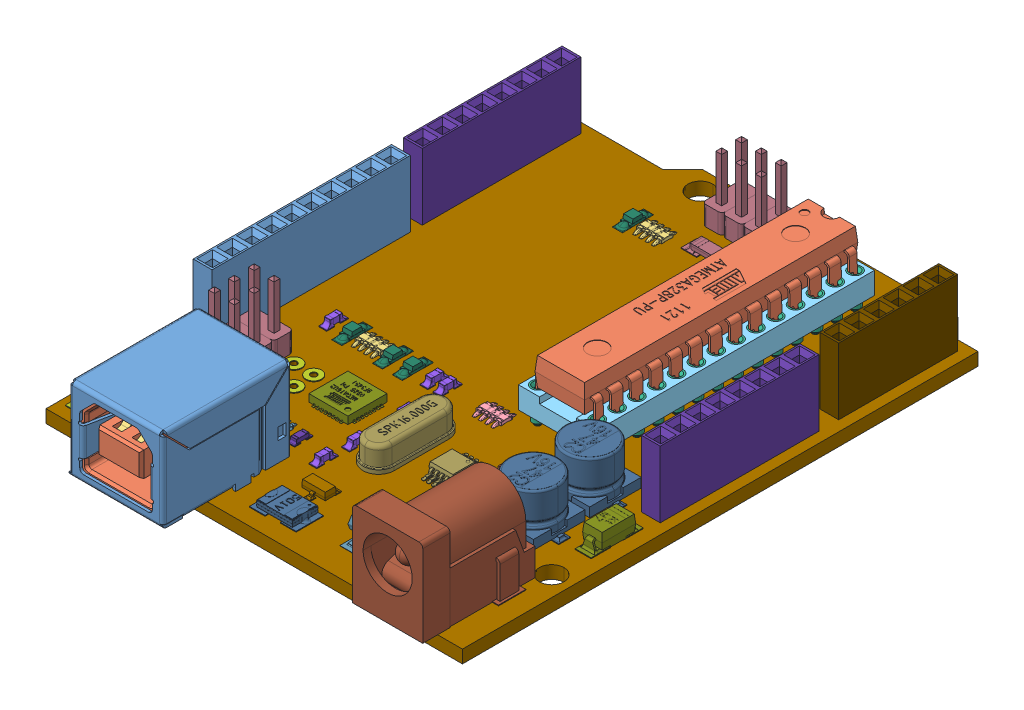
SolidWorks assembly arduino uno, configuration Default. Lengths in mm.
Overall size (53.34 15.26 74.94).
88 component instances, 35 part files, 0 mates.
Components (placement in the parent):
- arduino uno.STEP-1: arduino uno.STEP [Default] at origin size (53.34 15.26 74.94)
  - USB type b.STEP-1: USB type b.STEP [Default] at (-38.02 0.43 6.35) size (13.91 15.21 16.51)
    - USB SHELL.STEP-1: USB SHELL.STEP [Default] at origin size (13.91 15.21 16.51)
    - USB core.STEP-1: USB core.STEP [Default] at origin size (11.3 10.68 15.75)
    - usb top contact.STEP-1: usb top contact.STEP [Default] at (1.25 6.09 -0.38) size (1 9.67 13.76)
    - usb btm contact.STEP-1: usb btm contact.STEP [Default] at (1.25 4.41 -0.38) size (1 6.84 11.76)
    - usb btm contact.STEP-2: usb btm contact.STEP [Default] at (-1.25 4.41 -0.38) size (1 6.84 11.76)
    - usb top contact.STEP-2: usb top contact.STEP [Default] at (-1.25 6.09 -0.38) size (1 9.67 13.76)
  - dip28.STEP-1: dip28.STEP [Default] at (-16.383 1.5 -46.355) x (0 0 -1) z (1 0 0) size (35.48 7.37 10.1)
    - dip28-0.STEP-1: dip28-0.STEP [Default] at origin size (35.48 2.8 10.1)
    - dip socket pin.STEP-1: dip socket pin.STEP [Default] at (16.51 2.8 -3.81) size (1.7 7.37 1.7)
    - dip socket pin.STEP-2: dip socket pin.STEP [Default] at (16.51 2.8 3.81) size (1.7 7.37 1.7)
    - dip socket pin.STEP-3: dip socket pin.STEP [Default] at (13.97 2.8 -3.81) size (1.7 7.37 1.7)
    - dip socket pin.STEP-4: dip socket pin.STEP [Default] at (13.97 2.8 3.81) size (1.7 7.37 1.7)
    - dip socket pin.STEP-5: dip socket pin.STEP [Default] at (11.43 2.8 -3.81) size (1.7 7.37 1.7)
    - dip socket pin.STEP-6: dip socket pin.STEP [Default] at (11.43 2.8 3.81) size (1.7 7.37 1.7)
    - dip socket pin.STEP-7: dip socket pin.STEP [Default] at (8.89 2.8 -3.81) size (1.7 7.37 1.7)
    - dip socket pin.STEP-8: dip socket pin.STEP [Default] at (8.89 2.8 3.81) size (1.7 7.37 1.7)
    - dip socket pin.STEP-9: dip socket pin.STEP [Default] at (6.35 2.8 -3.81) size (1.7 7.37 1.7)
    - dip socket pin.STEP-10: dip socket pin.STEP [Default] at (6.35 2.8 3.81) size (1.7 7.37 1.7)
    - dip socket pin.STEP-11: dip socket pin.STEP [Default] at (3.81 2.8 -3.81) size (1.7 7.37 1.7)
    - dip socket pin.STEP-12: dip socket pin.STEP [Default] at (3.81 2.8 3.81) size (1.7 7.37 1.7)
    - dip socket pin.STEP-13: dip socket pin.STEP [Default] at (1.27 2.8 -3.81) size (1.7 7.37 1.7)
    - dip socket pin.STEP-14: dip socket pin.STEP [Default] at (1.27 2.8 3.81) size (1.7 7.37 1.7)
    - dip socket pin.STEP-15: dip socket pin.STEP [Default] at (-1.27 2.8 -3.81) size (1.7 7.37 1.7)
    - dip socket pin.STEP-16: dip socket pin.STEP [Default] at (-1.27 2.8 3.81) size (1.7 7.37 1.7)
    - dip socket pin.STEP-17: dip socket pin.STEP [Default] at (-3.81 2.8 -3.81) size (1.7 7.37 1.7)
    - dip socket pin.STEP-18: dip socket pin.STEP [Default] at (-3.81 2.8 3.81) size (1.7 7.37 1.7)
    - dip socket pin.STEP-19: dip socket pin.STEP [Default] at (-6.35 2.8 -3.81) size (1.7 7.37 1.7)
    - dip socket pin.STEP-20: dip socket pin.STEP [Default] at (-6.35 2.8 3.81) size (1.7 7.37 1.7)
    - dip socket pin.STEP-21: dip socket pin.STEP [Default] at (-8.89 2.8 -3.81) size (1.7 7.37 1.7)
    - dip socket pin.STEP-22: dip socket pin.STEP [Default] at (-8.89 2.8 3.81) size (1.7 7.37 1.7)
    - dip socket pin.STEP-23: dip socket pin.STEP [Default] at (-11.43 2.8 -3.81) size (1.7 7.37 1.7)
    - dip socket pin.STEP-24: dip socket pin.STEP [Default] at (-11.43 2.8 3.81) size (1.7 7.37 1.7)
    - dip socket pin.STEP-25: dip socket pin.STEP [Default] at (-13.97 2.8 -3.81) size (1.7 7.37 1.7)
    - dip socket pin.STEP-26: dip socket pin.STEP [Default] at (-13.97 2.8 3.81) size (1.7 7.37 1.7)
    - dip socket pin.STEP-27: dip socket pin.STEP [Default] at (-16.51 2.8 -3.81) size (1.7 7.37 1.7)
    - dip socket pin.STEP-28: dip socket pin.STEP [Default] at (-16.51 2.8 3.81) size (1.7 7.37 1.7)
  - RESET BUTTON.STEP-1: RESET BUTTON.STEP [Default] at (-49.403 0 -6.35) size (6.2 3.1 9.6)
    - RESET CORE.STEP-1: RESET CORE.STEP [Default] at (0 0.1 0) x (-1 0 0) z (0 0 -1) size (6.2 3.1 9.6)
    - RESET.STEP-1: RESET.STEP [Default] at (0 0.1 0) x (0 0 1) z (-1 0 0) size (7.3 2 6.2)
  - unoboard blue.STEP-1: unoboard blue.STEP [Default] at origin size (53.34 1.65 68.58)
  - 47uf CAP Dcase.STEP-1: 47uf CAP Dcase.STEP [Default] at (-9.4141 0 -18.4991) x (0 0 -1) z (1 0 0) size (6.6 5.81 8)
  - power jack.STEP-1: power jack.STEP [Default] at (-7.675 0 1.905) size (11.2 15.2 15.9)
  - 47uf CAP Dcase.STEP-2: 47uf CAP Dcase.STEP [Default] at (-9.4141 0 -25.7132) x (0 0 -1) z (1 0 0) size (6.6 5.81 8)
  - crystal.STEP-1: crystal.STEP [Default] at (-26.162 0 -18.923) x (1 0 0) z (0 0 -1) size (4 5 11)
  - 2pin_header__02.STEP-1: 2pin_header__02.STEP [Default] at (-46.23 0 -15.75) size (5 11.75 2.54)
  - nano - reg.STEP-1: nano - reg.STEP [Default] at (-17.399 0 -7.747) size (6.5 1.69 8.3)
  - led.STEP-1: led.STEP [Default] at (-34.29 0 -27.94) x (0 0 1) z (-1 0 0) size (4 0.85 1.47)
  - 2pin_header__02.STEP-2: 2pin_header__02.STEP [Default] at (-30.43 0 -64.91) x (0 0 1) z (-1 0 0) size (5 11.75 2.54)
  - 2pin_header__02.STEP-3: 2pin_header__02.STEP [Default] at (-27.89 0 -64.91) x (0 0 1) z (-1 0 0) size (5 11.75 2.54)
  - 2pin_header__02.STEP-4: 2pin_header__02.STEP [Default] at (-25.35 0 -64.91) x (0 0 1) z (-1 0 0) size (5 11.75 2.54)
  - 2pin_header__02.STEP-5: 2pin_header__02.STEP [Default] at (-46.23 0 -18.29) size (5 11.75 2.54)
  - 2pin_header__02.STEP-6: 2pin_header__02.STEP [Default] at (-46.23 0 -20.83) size (5 11.75 2.54)
  - atmega16u2.STEP-1: atmega16u2.STEP [Default] at (-34.671 0.06 -20) x (1 0 0) z (0 0 -1) size (5.5 1.01 5.5)
  - led.STEP-2: led.STEP [Default] at (-36.83 0 -27.94) x (0 0 1) z (-1 0 0) size (4 0.85 1.47)
  - led.STEP-3: led.STEP [Default] at (-42.037 0 -27.94) x (0 0 1) z (-1 0 0) size (4 0.85 1.47)
  - led.STEP-4: led.STEP [Default] at (-36.576 0 -58.42) x (0 0 1) z (-1 0 0) size (4 0.85 1.47)
  - 8 PORT HEADER.STEP-1: 8 PORT HEADER.STEP [Default] at (-50.8 0 -45.72) x (0 0 -1) z (1 0 0) size (20.32 10.51 2.41)
  - 8 PORT HEADER.STEP-2: 8 PORT HEADER.STEP [Default] at (-2.54 0 -27.94) x (0 0 -1) z (1 0 0) size (20.32 10.51 2.41)
  - 6 PORT HEADER.STEP-1: 6 PORT HEADER.STEP [Default] at (-2.54 0 -50.8) x (0 0 -1) z (1 0 0) size (15.24 10.51 2.41)
  - 10 PORT HEADER.STEP-1: 10 PORT HEADER.STEP [Default] at (-50.8 0 -18.796) x (0 0 -1) z (1 0 0) size (25.4 10.51 2.41)
  - ATMEL328P.STEP-1: ATMEL328P.STEP [Default] at (-16.383 4.3 -46.355) x (0 0 -1) z (1 0 0) size (35 7.27 7.87)
  - 102 RESISTOR PACK.STEP-1: 102 RESISTOR PACK.STEP [Default] at (-33.782 0 -58.42) size (3.2 0.46 3)
  - 102 RESISTOR PACK.STEP-2: 102 RESISTOR PACK.STEP [Default] at (-39.37 0 -27.94) size (3.2 0.46 3)
  - 103 RESISTOR PACK.STEP-1: 103 RESISTOR PACK.STEP [Default] at (-23.876 0 -27.94) size (3.2 0.46 3)
  - 220 RESISTOR PACK.STEP-1: 220 RESISTOR PACK.STEP [Default] at (-36.83 0 -12.827) size (3.2 0.46 3)
  - 16mhz crystal - measured.STEP-1: 16mhz crystal - measured.STEP [Default] at (-24.892 0 -41.275) x (0 0 -1) z (1 0 0) size (3.4 0.8 2)
  - PADS001.STEP-1: PADS001.STEP [Default] at (-39.878 0.1 -18.288) x (-1 0 0) z (0 0 1) size (4.54 0.1 4.54)
  - 603 cap on pad.STEP-1: 603 cap on pad.STEP [Default] at (-44.45 0 -27.94) x (0 0 -1) z (1 0 0) size (2.76 0.9 1.03)
  - ssot3.STEP-1: ssot3.STEP [Default] at (-26.5 0 -8.128) x (-1 0 0) z (0 0 -1) size (3 1.13 3.09)
  - mf-msmf050-2.STEP-1: mf-msmf050-2.STEP [Default] at (-26.5 0 -4.064) size (5.86 1.02 3.72)
  - 603 cap on pad.STEP-2: 603 cap on pad.STEP [Default] at (-29.845 0 -27.94) x (0 0 -1) z (1 0 0) size (2.76 0.9 1.03)
  - 603 cap on pad.STEP-3: 603 cap on pad.STEP [Default] at (-31.496 0 -27.94) x (0 0 -1) z (1 0 0) size (2.76 0.9 1.03)
  - lmv358.STEP-1: lmv358.STEP [Default] at (-15.24 0 -21.971) x (0 0 -1) z (1 0 0) size (3.7 1.4 2.9)
  - 603 cap on pad.STEP-4: 603 cap on pad.STEP [Default] at (-15.24 0 -18.415) size (2.76 0.9 1.03)
  - 603 cap on pad.STEP-5: 603 cap on pad.STEP [Default] at (-29.845 0 -12.065) x (0 0 1) z (-1 0 0) size (2.76 0.9 1.03)
  - 603 cap on pad.STEP-6: 603 cap on pad.STEP [Default] at (-29.591 0 -22.352) x (0 0 1) z (-1 0 0) size (2.76 0.9 1.03)
  - 603 cap on pad.STEP-7: 603 cap on pad.STEP [Default] at (-29.591 0 -16.002) x (0 0 1) z (-1 0 0) size (2.76 0.9 1.03)
  - 603 cap on pad.STEP-8: 603 cap on pad.STEP [Default] at (-41.91 0 -12.7) x (0 0 1) z (-1 0 0) size (2.76 0.9 1.03)
  - lp2985dgkr.STEP-1: lp2985dgkr.STEP [Default] at (-20.32 0 -19.05) x (0 0 -1) z (1 0 0) size (5.85 1.1 3)
  - cd1206 diode.STEP-1: cd1206 diode.STEP [Default] at (-27.94 0 -59.436) x (0 0 -1) z (1 0 0) size (2.01 0.96 5)
  - cd1206 diode.STEP-2: cd1206 diode.STEP [Default] at (-46.228 0 -13.081) x (0 0 1) z (-1 0 0) size (2.01 0.96 5)
  - 603 resistor.STEP-1: 603 resistor.STEP [Default] at (-29.591 0 -19.05) x (0 0 1) z (-1 0 0) size (2.36 0.61 1.02)
  - blm21.STEP-1: blm21.STEP [Default] at (-45.085 0 -7.62) x (0 0 -1) z (1 0 0) size (2.78 0.95 1.32)
  - m7 diode.STEP-1: m7 diode.STEP [Default] at (-2.794 0 -21.59) x (0 0 -1) z (1 0 0) size (6.66 2.35 2.5)
  - MLC0603.STEP-1: MLC0603.STEP [Default] at (-33.655 0 -12.827) x (0 0 -1) z (1 0 0) size (2.36 0.6 1.02)
  - MLC0603.STEP-2: MLC0603.STEP [Default] at (-39.37 0 -12.827) x (0 0 -1) z (1 0 0) size (2.36 0.6 1.02)
